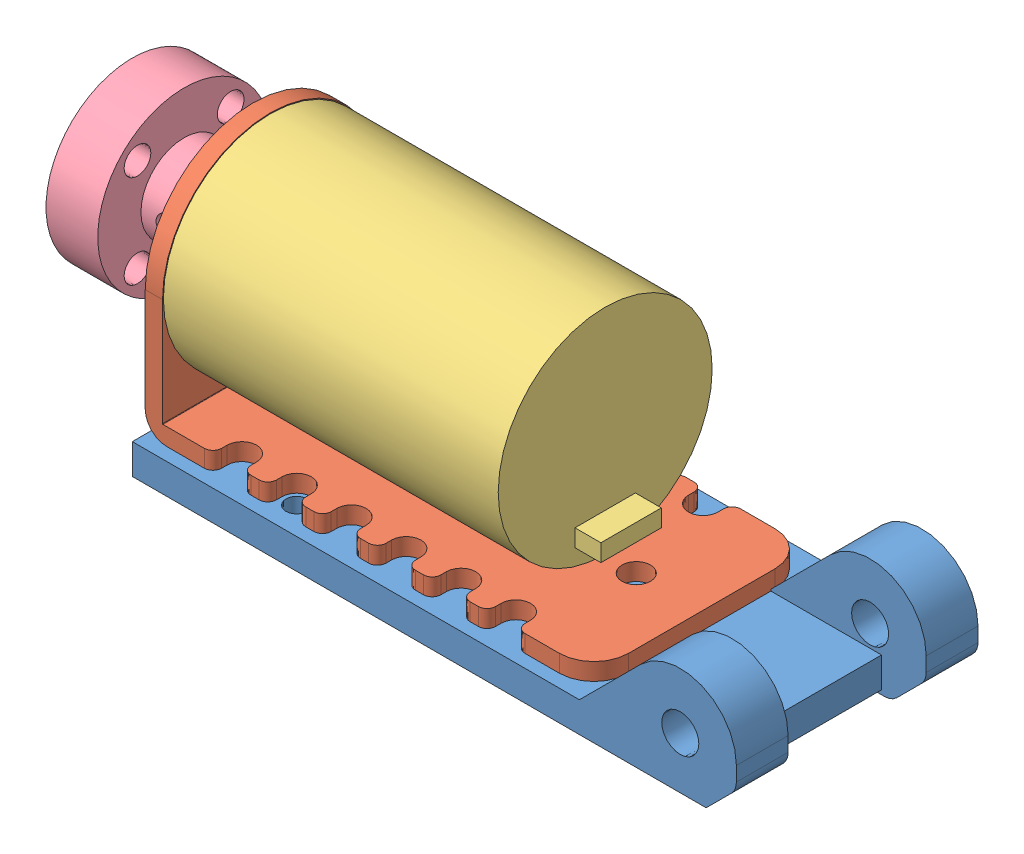
SolidWorks assembly Motor Assembly, configuration Standard. Lengths in mm.
Overall size (84 31 28).
4 component instances, 4 part files, 8 mates.
Components (placement in the parent):
- Motor Mount-1: Motor Mount [Standard] at origin size (70 13 28)
- Motor Mount Plate-1: Motor Mount Plate [Standard] at (-33 4 12.5) size (52 27 25)
- Motor-1: Motor [Standard] at (5.8 18.5 0) x (0 0 1) z (-1 0 0) size (24.8 24.8 53.8)
- WheelHub2-1: WheelHub2 [Standard] at (-49 18.5 0) x (0 -1 0) z (0 0 1) size (20 12 20)
Mates (geometry in assembly coordinates):
- Deckungsgleich1: coincident anti-aligned: plane of Motor Mount-1 through (0 4 0) normal (0 1 0); plane of Motor Mount Plate-1 through (-33 4 -12.5) normal (0 -1 0)
- Abstand1: distance = 1.5 mm: line of Motor Mount Plate-1 through (-32.5 4 -12.5) axis (1 0 0); line of Motor Mount-1 through (16.8076 4 -14) axis (-1 0 0)
- Deckungsgleich5: coincident aligned: plane of Motor Mount-1 through (-35 4 -14) normal (-1 0 0); plane of Motor Mount Plate-1 through (-35 31 -12.5) normal (-1 0 0)
- Deckungsgleich7: coincident anti-aligned: circle of Motor Mount Plate-1; circle of Motor-1
- Konzentrisch2: concentric anti-aligned: circle of Motor-1; circle of ?
- Abstand2: distance = 1 mm anti-aligned: plane of Motor Mount Plate-1 through (-35 31 -12.5) normal (-1 0 0); plane of ? through (-36 18.5 0) normal (1 0 0)
- Konzentrisch3: concentric anti-aligned: circle of Motor-1; circle of WheelHub2-1
- Abstand3: distance = 2 mm anti-aligned: plane of WheelHub2-1 through (-37 18.5 0) normal (1 0 0); plane of Motor Mount Plate-1 through (-35 31 -12.5) normal (-1 0 0)
